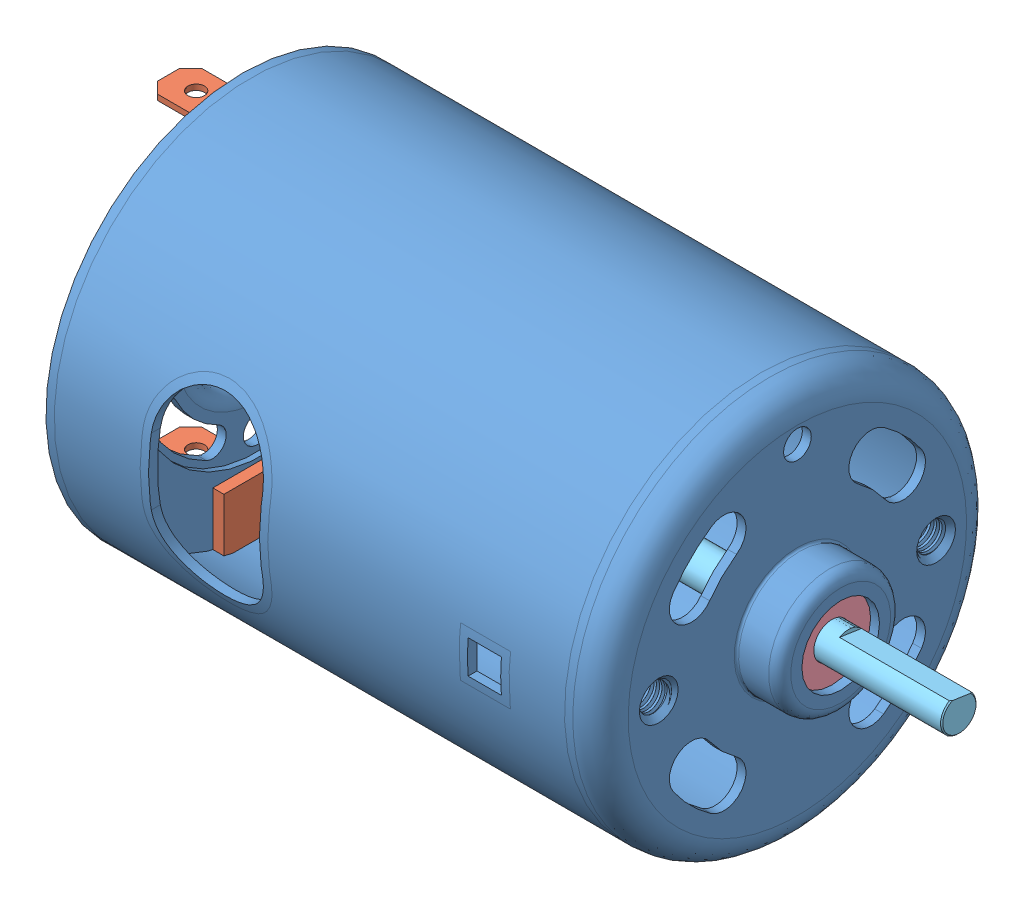
SolidWorks assembly 540_Motor, configuration Default. Lengths in mm.
Overall size (71.3 35.5 35.5).
6 component instances, 5 part files, 14 mates.
Components (placement in the parent):
- Motor_case-1: Motor_case [Default] at (21.6629 -4.0805 -8.659) size (56.9 35.5 35.5)
- Motor_terminal-1: Motor_terminal [Default] at (-26.5371 -18.0805 -8.659) x (0 0 1) z (0 -1 0) size (9 9.5 5)
- Motor_terminal-2: Motor_terminal [Default] at (-26.5371 9.9195 -8.659) x (0 0 -1) z (0 1 0) size (9 9.5 5)
- Motor_rear_brush-1: Motor_rear_brush [Default] at (-31.0871 -4.0805 -8.659) x (1 0 0) z (0 -0.06575 0.997836) size (2.75 7.25 7.25)
- Motor_front_brush-1: Motor_front_brush [Default] at (23.3129 -4.0805 -8.659) size (2.9 9.4 9.4)
- Motor_shaft-1: Motor_shaft [Default] at (36.2629 -4.0805 -8.659) x (0 0.146436 0.98922) z (-1 0 0) size (3.2 3.2 70)
Mates (geometry in assembly coordinates):
- Coincident1: coincident: plane of assembly; plane of assembly; plane of Motor_terminal-1 through (-25.5371 -18.0805 -8.659) normal (1 0 0); plane of Motor_terminal-2 through (-25.5371 9.9195 -8.659) normal (1 0 0)
- Coincident2: coincident: plane of assembly; plane of assembly; plane of Motor_case-1 through (-26.5371 7.1195 -8.659) normal (1 0 0); plane of Motor_terminal-2 through (-26.5371 9.9195 -8.659) normal (-1 0 0)
- Width1: width: plane of assembly; plane of assembly; plane of assembly; plane of assembly; plane of Motor_terminal-1 through (-28.0371 -19.5805 -12.159) normal (0 -1 0); plane of Motor_terminal-1 through (-28.0371 -16.5805 -12.159) normal (0 1 0); plane of Motor_case-1 through (25.5639 -19.5805 -12.159) normal (0 1 0); plane of Motor_case-1 through (25.5639 -16.5805 -12.159) normal (0 -1 0)
- Width2: width: plane of assembly; plane of assembly; plane of assembly; plane of assembly; plane of Motor_case-1 through (25.5639 -19.5805 -5.159) normal (0 0 -1); plane of Motor_case-1 through (25.5639 -19.5805 -12.159) normal (0 0 1); plane of Motor_terminal-1 through (-28.0371 -16.5805 -5.159) normal (0 0 1); plane of Motor_terminal-1 through (-28.0371 -16.5805 -12.159) normal (0 0 -1)
- Width3: width: plane of assembly; plane of assembly; plane of assembly; plane of assembly; plane of Motor_terminal-2 through (-28.0371 8.4195 -5.159) normal (0 0 1); plane of Motor_terminal-2 through (-28.0371 8.4195 -12.159) normal (0 0 -1); plane of Motor_case-1 through (25.5639 11.4195 -5.159) normal (0 0 -1); plane of Motor_case-1 through (25.5639 11.4195 -12.159) normal (0 0 1)
- Width4: width: plane of assembly; plane of assembly; plane of assembly; plane of assembly; plane of Motor_case-1 through (25.5639 8.4195 -12.159) normal (0 1 0); plane of Motor_case-1 through (25.5639 11.4195 -12.159) normal (0 -1 0); plane of Motor_terminal-2 through (-28.0371 8.4195 -5.159) normal (0 -1 0); plane of Motor_terminal-2 through (-28.0371 11.4195 -5.159) normal (0 1 0)
- Concentric1: concentric: cylinder of assembly; cylinder of assembly; cylinder of Motor_case-1 through (21.6629 -4.0805 -8.659) axis (1 0 0) radius 3.625; cylinder of Motor_rear_brush-1 through (-36.0821 -4.0805 -8.659) axis (-1 0 0) radius 1.625
- Coincident3: coincident: circle of assembly; plane of assembly; circle of Motor_case-1; plane of Motor_rear_brush-1 through (-31.0871 -1.2117 -8.4699) normal (-1 0 0)
- Concentric2: concentric: cylinder of assembly; cylinder of assembly; cylinder of Motor_case-1 through (21.6629 -4.0805 -8.659) axis (1 0 0) radius 4.7; cylinder of Motor_front_brush-1 through (27.4502 -4.0805 -8.659) axis (1 0 0) radius 1.625
- Coincident4: coincident: circle of assembly; plane of assembly; circle of Motor_case-1; plane of Motor_front_brush-1 through (24.7629 -2.4555 -8.659) normal (1 0 0)
- Concentric3: concentric: cylinder of assembly; cylinder of assembly; cylinder of Motor_front_brush-1 through (27.4502 -4.0805 -8.659) axis (1 0 0) radius 1.625; cylinder of Motor_shaft-1 through (-33.7371 -4.0805 -8.659) axis (1 0 0) radius 1.6
- Distance1: distance = 10.7 mm: plane of assembly; plane of assembly; plane of Motor_shaft-1 through (36.2629 -4.0805 -8.659) normal (1 0 0); plane of Motor_case-1 through (25.5629 -0.5805 -8.659) normal (1 0 0)
- Concentric5: concentric: cylinder of ? through (-33.7371 -4.0805 -8.659) axis (1 0 0) radius 1.6; cylinder of ? through (26.2629 -4.0805 -8.659) axis (1 0 0) radius 1.5
- Coincident5: coincident: plane of ? through (36.2629 -4.0805 -8.659) normal (1 0 0); plane of ? through (36.2629 -4.0805 -8.659) normal (1 0 0)
